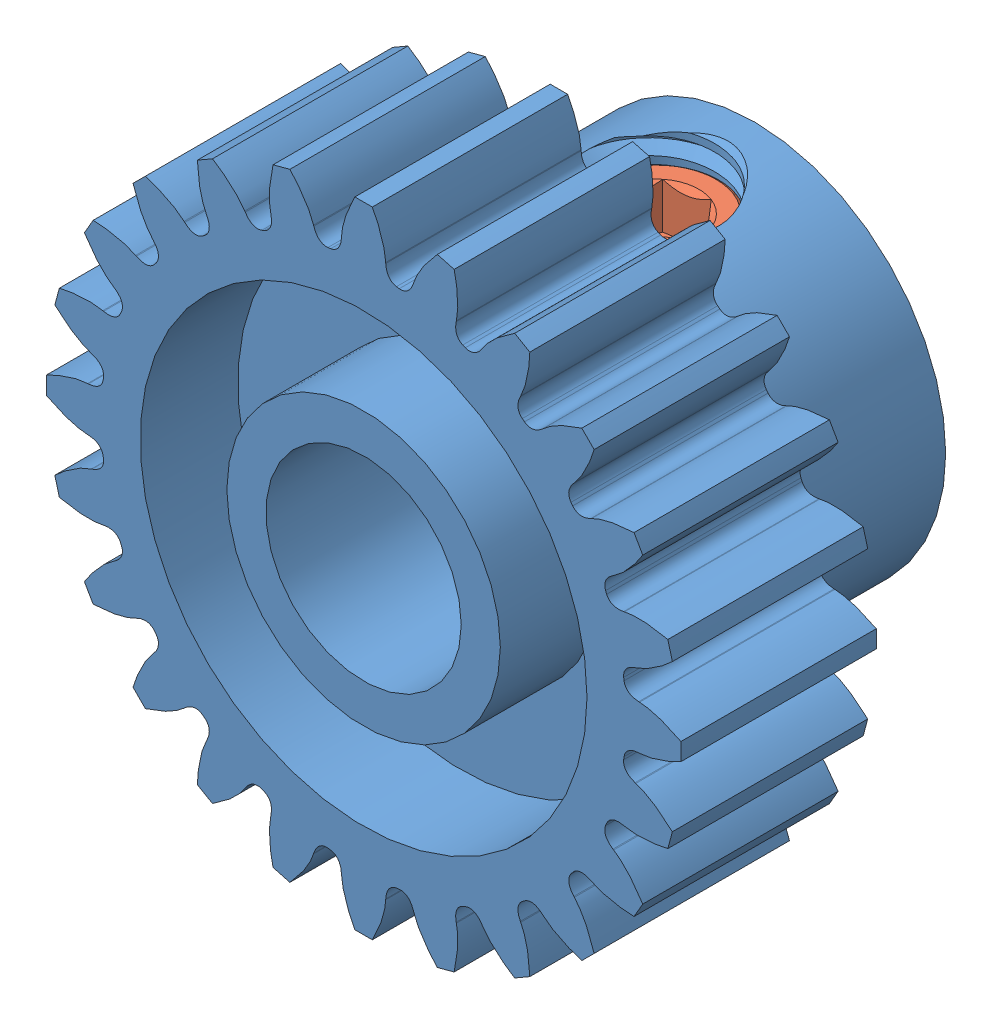
SolidWorks assembly 615250 - GEAR, PINION, .250 BORE, 32 PITCH, .75 PD, 24 TOOTH, .813 OD, BRASS, SERVOCITY, configuration Default. Lengths in mm.
Overall size (20.64 20.64 12.7).
2 component instances, 2 part files, 0 mates.
Components (placement in the parent):
- 615250_Gear Blank-1: 615250_Gear Blank [Default] at (-20.5638 19.7198 -0.8707) size (20.64 20.64 12.7)
- 632134_91375A436-1: 632134_91375A436 [Default] at (-20.5638 23.7539 -4.0457) x (0.934645 0 0.355583) z (0 1 0) size (4.98 4.83 3.31)
